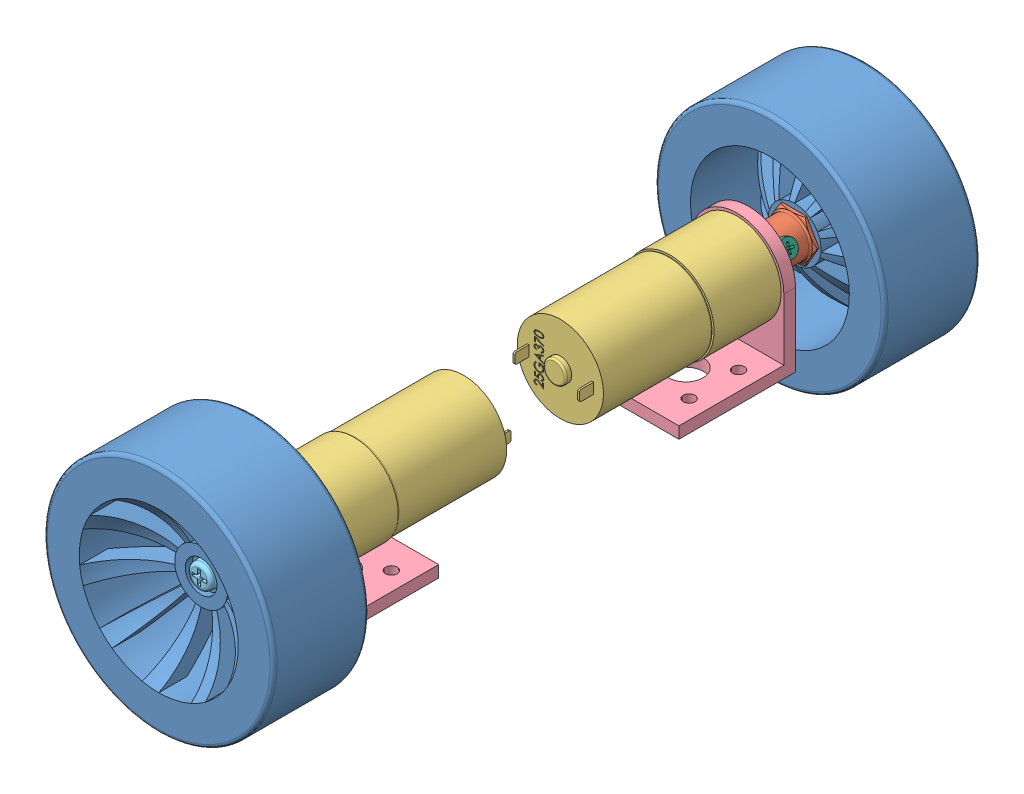
SolidWorks assembly 车轮部分, configuration 默认. Lengths in mm.
Overall size (65 65 200).
18 component instances, 6 part files, 28 mates.
Components (placement in the parent):
- 橡胶车轮-1: 橡胶车轮 [默认] at (-23.5255 18.6367 15) size (65 65 27)
- 内六角联轴器-1: 内六角联轴器 [默认] at (-23.5255 18.6367 21) x (-0.866025 -0.5 0) z (0 0 -1) size (12 13.86 18)
- 25GA370-1: 25GA370 [Default] at (-23.5255 18.6367 55.3) x (0 1 0) z (0 0 1) size (25 25 66)
- 25GA370支撑架-1: 25GA370支撑架 [默认] at (-23.5255 18.6367 36.3) x (-1 0 0) z (0 0 -1) size (26.5 34 33)
- 25GA370支撑架-2: 25GA370支撑架 [默认] at (-23.5255 18.6367 163.7) size (26.5 34 33)
- 内六角联轴器-2: 内六角联轴器 [默认] at (-23.5255 18.6367 179) x (0.866025 0.5 0) z (0 0 1) size (12 13.86 18)
- 25GA370-2: 25GA370 [Default] at (-23.5255 18.6367 144.7) x (0 -1 0) z (0 0 -1) size (25 25 66)
- 橡胶车轮-3: 橡胶车轮 [默认] at (-23.5255 18.6367 185) x (-1 0 0) z (0 0 -1) size (65 65 27)
- cross recessed cheese head screws gb-2: cross recessed cheese head screws gb [GB_CROSS_SCREWS_TYPE2 M4X8-8  H type-N] at (-23.5255 18.6367 188.6) x (0 0 -1) z (1 0 0) size (10.6 7 7)
- cross recessed cheese head screws gb-4: cross recessed cheese head screws gb [GB_CROSS_SCREWS_TYPE2 M3X5-5  H type-C] at (-15.0255 18.6367 31) x (0 0 1) z (-1 0 0) size (7.01 5.5 5.5)
- cross recessed cheese head screws gb-5: cross recessed cheese head screws gb [GB_CROSS_SCREWS_TYPE2 M3X5-5  H type-C] at (-32.0255 18.6367 31) x (0 0 1) z (-1 0 0) size (7.01 5.5 5.5)
- cross recessed cheese head screws type a gb-1: cross recessed cheese head screws type a gb [GB_CROSS_SCREWS_TYPE135 M3X4-C] at (-17.1169 22.3367 28) x (-0.866025 -0.5 0) z (0.080887 -0.1401 -0.986828) size (5.4 4.98 4.98)
- cross recessed cheese head screws type a gb-2: cross recessed cheese head screws type a gb [GB_CROSS_SCREWS_TYPE135 M3X4-C] at (-29.9341 14.9367 28) x (0.866025 0.5 0) z (-0.198904 0.344512 0.917469) size (5.4 4.98 4.98)
- cross recessed cheese head screws gb-6: cross recessed cheese head screws gb [GB_CROSS_SCREWS_TYPE2 M4X8-8  H type-N] at (-23.5255 18.6367 11.4) x (0 0 1) z (-1 0 0) size (10.6 7 7)
- cross recessed cheese head screws type a gb-3: cross recessed cheese head screws type a gb [GB_CROSS_SCREWS_TYPE135 M3X4-C] at (-29.9341 14.9367 172) x (0.866025 0.5 0) z (0.198904 -0.344512 0.917469) size (5.4 4.98 4.98)
- cross recessed cheese head screws type a gb-4: cross recessed cheese head screws type a gb [GB_CROSS_SCREWS_TYPE135 M3X4-C] at (-17.1169 22.3367 172) x (-0.866025 -0.5 0) z (-0.080887 0.1401 -0.986828) size (5.4 4.98 4.98)
- cross recessed cheese head screws gb-7: cross recessed cheese head screws gb [GB_CROSS_SCREWS_TYPE2 M3X5-5  H type-C] at (-32.0255 18.6367 169) x (0 0 -1) z (1 0 0) size (7.01 5.5 5.5)
- cross recessed cheese head screws gb-8: cross recessed cheese head screws gb [GB_CROSS_SCREWS_TYPE2 M3X5-5  H type-C] at (-15.0255 18.6367 169) x (0 0 -1) z (1 0 0) size (7.01 5.5 5.5)
Mates (geometry in assembly coordinates):
- 重合2: coincident anti-aligned: plane of 橡胶车轮-1 through (-23.5255 18.6367 0) normal (0 0 -1)
- 重合3: coincident anti-aligned: plane of 橡胶车轮-1 through (-23.5255 18.6367 15) normal (0 0 1); plane of 内六角联轴器-1 through (-23.5255 18.6367 15) normal (0 0 -1)
- 重合4: coincident anti-aligned: plane of 橡胶车轮-1 through (-26.9896 24.6367 20) normal (0.866025 -0.5 0); plane of 内六角联轴器-1 through (-30.4537 18.6367 15) normal (-0.866025 0.5 0)
- 重合5: coincident anti-aligned: plane of 橡胶车轮-1 through (-26.9896 12.6367 20) normal (0 1 0); plane of 内六角联轴器-1 through (-20.0614 12.6367 15) normal (0 -1 0)
- 同心1: concentric aligned: cylinder of 内六角联轴器-1 through (-23.5255 18.6367 21) axis (0 0 1) radius 2; cylinder of 25GA370-1 through (-23.5255 18.6367 24.3) axis (0 0 1) radius 2
- 重合10: coincident anti-aligned: plane of 25GA370-1 through (-23.5255 18.6367 36.3) normal (0 0 -1); plane of 25GA370支撑架-1 through (-23.5255 18.6367 36.3) normal (0 0 1)
- 同心3: concentric aligned: cylinder of 25GA370-1 through (-23.5255 18.6367 33.8) axis (0 0 1) radius 3.5; cylinder of 25GA370支撑架-1 through (-23.5255 18.6367 33) axis (0 0 1) radius 4
- 平行4: parallel anti-aligned: plane of 25GA370支撑架-1 through (-10.2755 -2.1133 33) normal (0 -1 0)
- 同心4: concentric anti-aligned: cylinder of 25GA370-1 through (-32.0255 18.6367 36.3) axis (0 0 -1) radius 1.25; cylinder of 25GA370支撑架-1 through (-32.0255 18.6367 33) axis (0 0 1) radius 1.5
- 同心5: concentric anti-aligned: cylinder of 25GA370-1 through (-15.0255 18.6367 36.3) axis (0 0 -1) radius 1.25; cylinder of 25GA370支撑架-1 through (-15.0255 18.6367 33) axis (0 0 1) radius 1.5
- 重合11: coincident anti-aligned: plane of 内六角联轴器-2 through (-23.5255 18.6367 185) normal (0 0 1); plane of 橡胶车轮-3 through (-23.5255 18.6367 185) normal (0 0 -1)
- 重合12: coincident anti-aligned: plane of 内六角联轴器-2 through (-16.5973 18.6367 185) normal (0.866025 0.5 0); plane of 橡胶车轮-3 through (-20.0614 24.6367 180) normal (-0.866025 -0.5 0)
- 重合13: coincident anti-aligned: plane of 内六角联轴器-2 through (-20.0614 24.6367 185) normal (0 1 0); plane of 橡胶车轮-3 through (-26.9896 24.6367 180) normal (0 -1 0)
- 重合14: coincident anti-aligned: plane of 橡胶车轮-3 through (-23.5255 18.6367 186) normal (0 0 1); plane of cross recessed cheese head screws gb-2 through (-23.5255 20.9367 186) normal (0 0 -1)
- 同心6: concentric anti-aligned: cylinder of 内六角联轴器-2 through (-23.5255 18.6367 185) axis (0 0 1) radius 1.65; cylinder of cross recessed cheese head screws gb-2 through (-23.5255 18.6367 184.0842) axis (0 0 -1) radius 2
- 重合15: coincident anti-aligned: plane of 橡胶车轮-1 through (-23.5255 18.6367 14) normal (0 0 -1); plane of cross recessed cheese head screws gb-3 through (-23.5255 20.9367 14) normal (0 0 1)
- 同心7: concentric anti-aligned: cylinder of 内六角联轴器-1 through (-23.5255 18.6367 15) axis (0 0 -1) radius 1.65; cylinder of cross recessed cheese head screws gb-3 through (-23.5255 18.6367 15.9158) axis (0 0 1) radius 2
- 重合16: coincident anti-aligned: plane of 25GA370支撑架-1 through (-23.5255 18.6367 33) normal (0 0 -1); plane of cross recessed cheese head screws gb-5 through (-32.0255 20.4367 33) normal (0 0 1)
- 同心8: concentric aligned: cylinder of 25GA370支撑架-1 through (-32.0255 18.6367 33) axis (0 0 1) radius 1.5; cylinder of cross recessed cheese head screws gb-5 through (-32.0255 18.6367 35.5158) axis (0 0 1) radius 1.5
- 重合17: coincident anti-aligned: plane of 25GA370支撑架-1 through (-23.5255 18.6367 33) normal (0 0 -1); plane of cross recessed cheese head screws gb-4 through (-15.0255 20.4367 33) normal (0 0 1)
- 同心9: concentric aligned: cylinder of 25GA370支撑架-1 through (-15.0255 18.6367 33) axis (0 0 1) radius 1.5; cylinder of cross recessed cheese head screws gb-4 through (-15.0255 18.6367 35.5158) axis (0 0 1) radius 1.5
- 同心10: concentric anti-aligned: cylinder of 内六角联轴器-1 through (-23.5255 18.6367 28) axis (-0.866025 -0.5 0) radius 1.65; cylinder of cross recessed cheese head screws type a gb-1 through (-21.7934 19.6367 28) axis (0.866025 0.5 0) radius 1.5
- 相切2: tangent anti-aligned: cylinder of 内六角联轴器-1 through (-23.5255 18.6367 21) axis (0 0 1) radius 2; plane of cross recessed cheese head screws type a gb-1 through (-21.7934 19.6367 28) normal (-0.866025 -0.5 0)
- 相切4: tangent anti-aligned: cylinder of 内六角联轴器-1 through (-23.5255 18.6367 21) axis (0 0 1) radius 2; plane of cross recessed cheese head screws type a gb-2 through (-25.2575 17.6367 28) normal (0.866025 0.5 0)
- 同心12: concentric anti-aligned: cylinder of 内六角联轴器-1 through (-23.5255 18.6367 28) axis (0.866025 0.5 0) radius 1.65; cone of cross recessed cheese head screws type a gb-2 through (-27.8556 16.1367 28) axis (-0.866025 -0.5 0)
- 重合19: coincident anti-aligned: plane of 25GA370支撑架-1 through (-36.7755 1.1867 66) normal (0 1 0); plane of 第一层(2)(1)-1 through (105.9795 1.1867 100.0469) normal (0 -1 0)
- 平行5: parallel aligned: plane of 25GA370支撑架-1 through (-23.5255 18.6367 33) normal (0 0 -1); plane of 第一层(2)(1)-1 through (-56.5205 5.1867 40.0469) normal (0 0 -1)
- 重合20: coincident anti-aligned: plane of 25GA370支撑架-2 through (-23.5255 18.6367 167) normal (0 0 1); plane of 内六角联轴器-2 through (-23.5255 18.6367 167) normal (0 0 -1)
